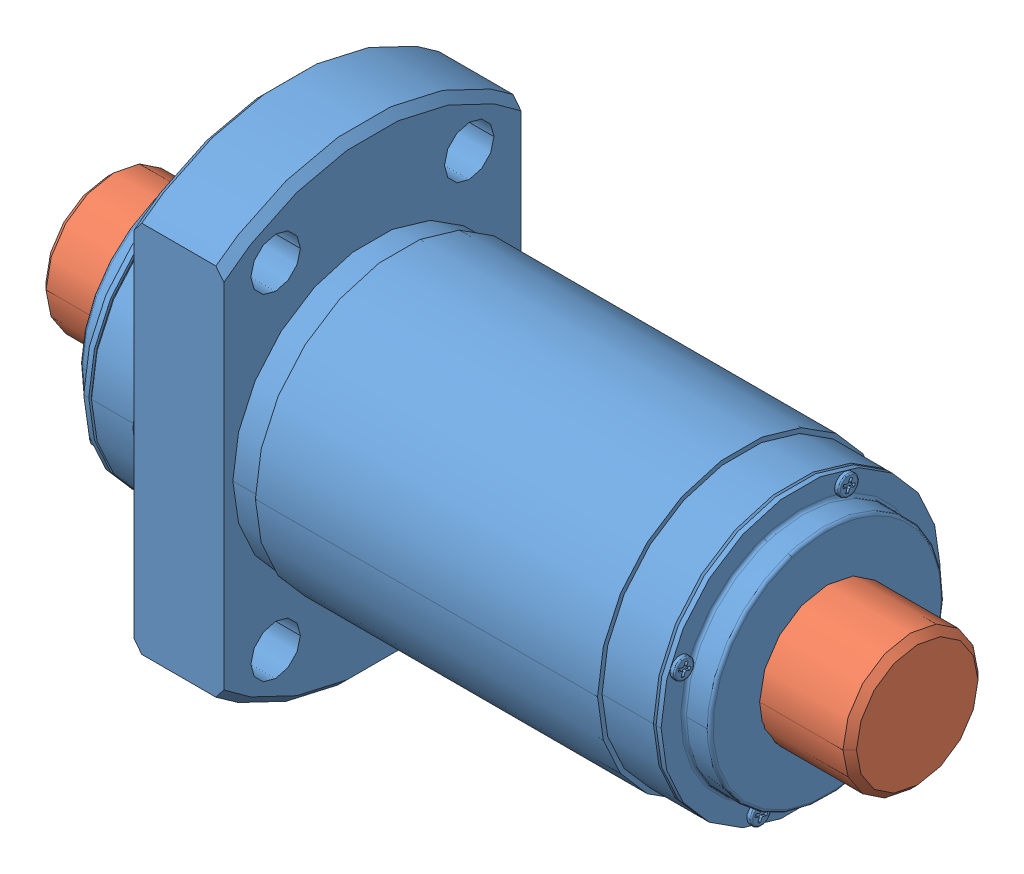
SolidWorks assembly WTF1530_3ZZ_90LC7T_000, configuration Default. Lengths in mm.
Overall size (90 53 34.14).
2 component instances, 2 part files, 0 mates.
Components (placement in the parent):
- WTF1530_3ZZ_90LC7T_000_3-1: WTF1530_3ZZ_90LC7T_000_3 [Default] at (13.5 0 0) size (70 53 34.14)
- WTF1530_3ZZ_90LC7T_000_5-1: WTF1530_3ZZ_90LC7T_000_5 [Default] at origin size (90 15 15)
